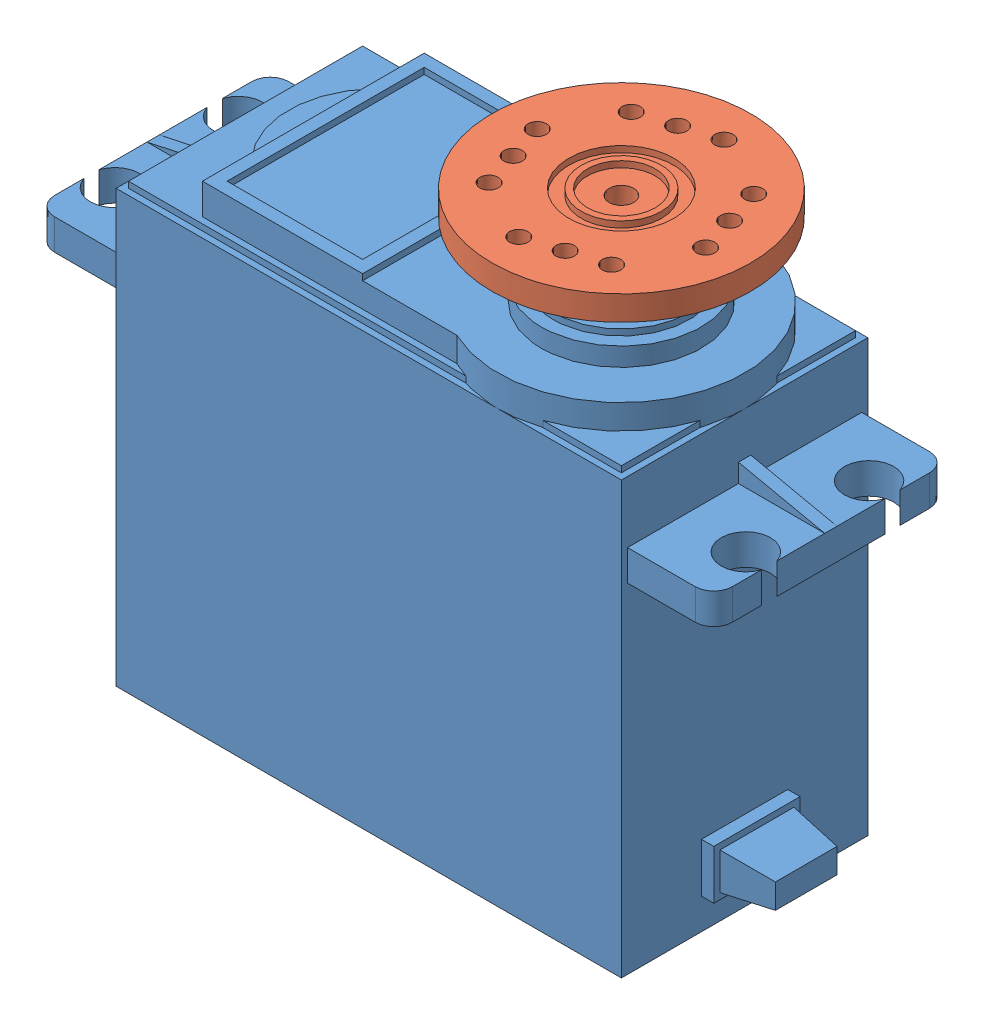
SolidWorks assembly mg996r_plate, configuration Default. Lengths in mm.
Overall size (55 47.5 26.36).
2 component instances, 2 part files, 2 mates.
Components (placement in the parent):
- mg996r-1: mg996r [Default] at (8.1041 3.8249 50.2193) size (55 45.5 20)
- rc plate-1: rc plate [Default] at (18.6041 51.3249 50.2193) x (-0.953412 0 0.301672) z (0.301672 0 0.953412) size (21 5 21)
Mates (geometry in assembly coordinates):
- Concentric1: concentric: cylinder of mg996r-1 through (18.6041 49.3249 50.2193) axis (0 -1 0) radius 3; cylinder of rc plate-1 through (18.6041 46.3249 50.2193) axis (0 1 0) radius 3
- Coincident1: coincident: plane of mg996r-1 through (18.6041 49.3249 50.2193) normal (0 1 0); plane of rc plate-1 through (18.6041 49.3249 50.2193) normal (0 -1 0)
